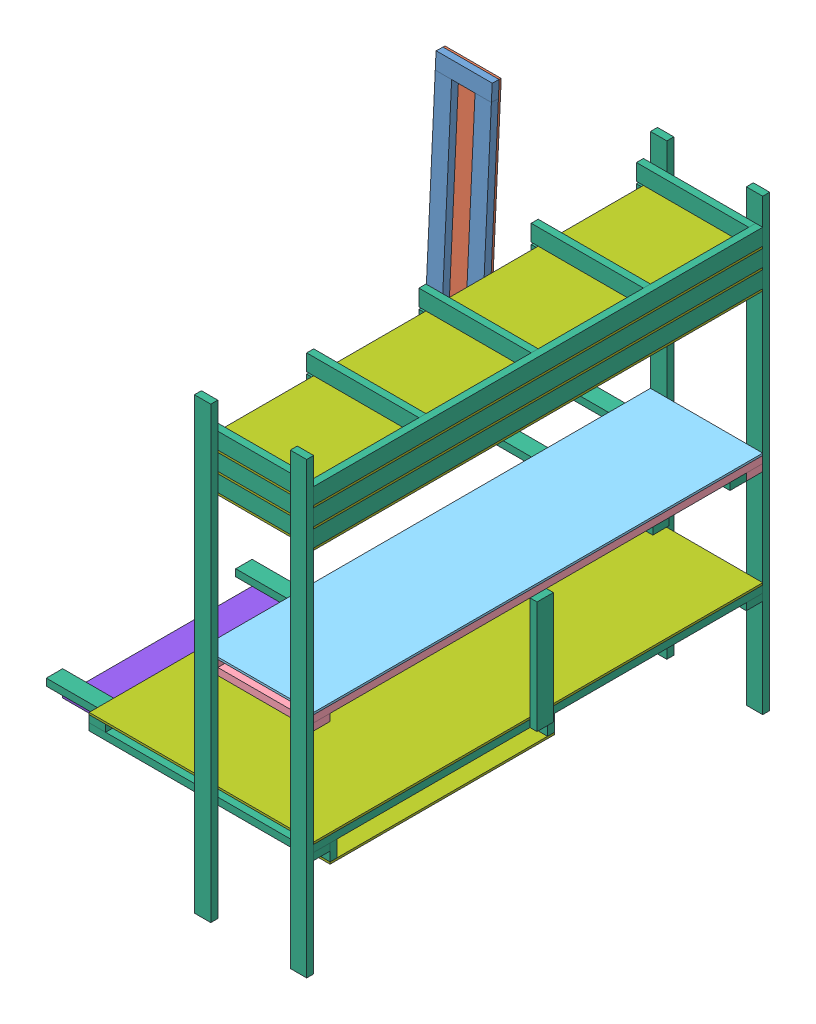
SolidWorks assembly Crafting, configuration Default. Lengths in mm.
Overall size (1623.82 2790.53 2514.6).
67 component instances, 9 part files, 18 mates.
Components (placement in the parent):
- PlotterSupport-1: PlotterSupport [Default] at (-703.0452 -398.7417 -1142.4773) size (304.8 1609.43 541.53)
  - 2x4_Plotter-1: 2x4_Plotter [PlotterWidth] at (215.9 150.676 537.183) x (1 0 0) z (0 0.998805 -0.048876) size (88.9 38.1 1371.6)
  - 2x4_Plotter-2: 2x4_Plotter [PlotterWidth] at (0 150.676 537.183) x (1 0 0) z (0 0.998805 -0.048876) size (88.9 38.1 1371.6)
  - 2x4_Plotter-3: 2x4_Plotter [PlotterDepth] at (304.8 1520.6367 470.144) x (0 0.998805 -0.048876) z (-1 0 0) size (88.9 38.1 304.8)
  - 2x4_Plotter-4: 2x4_Plotter [PlotterDepth] at (0 150.676 537.183) x (0 -0.998805 0.048876) z (1 0 0) size (88.9 38.1 304.8)
  - 2x4_Plotter-5: 2x4_Plotter [PlotterDepth] at (0 0 508) x (0 0 -1) z (1 0 0) size (88.9 38.1 304.8)
  - 2x4_Plotter-6: 2x4_Plotter [PlotterBase] at (215.9 0 88.9) size (88.9 38.1 330.2)
  - 2x4_Plotter-7: 2x4_Plotter [PlotterBase] at (0 0 88.9) size (88.9 38.1 330.2)
  - Plywood_Plotter-1: Plywood_Plotter [PlotterDepth-X-PlotterWidth] at (0 59.4769 492.3744) x (1 0 0) z (0 0.048876 0.998805) size (304.8 1549.4 11.11)
  - Plywood_Plotter-2: Plywood_Plotter [PlotterDepth-X-PlotterBase] at (0 49.2125 0) x (1 0 0) z (0 -1 0) size (304.8 482.6 11.11)
  - Hinge-3: Hinge [Reverse] at (304.8 51.8795 490.076) x (0 0.998805 -0.048876) z (-1 0 0) size (53.98 15.88 101.6)
  - Hinge-4: Hinge [Reverse] at (101.6 51.8795 490.076) x (0 0.998805 -0.048876) z (-1 0 0) size (53.98 15.88 101.6)
  - Hinge-5: Hinge [Default] at (203.2 51.8795 490.076) x (0 0 -1) z (1 0 0) size (53.98 15.88 101.6)
  - Hinge-6: Hinge [Default] at (0 51.8795 490.076) x (0 0 -1) z (1 0 0) size (53.98 15.88 101.6)
  - 2x4_Plotter-9: 2x4_Plotter [PlotterDepth] at (0 0 88.9) x (0 0 -1) z (1 0 0) size (88.9 38.1 304.8)
- Printers-1: Printers [Default] at (259.4601 -401.6094 -1116.5989) x (0 0 1) z (-1 0 0) size (2438.4 87.31 609.6)
  - 2x4_Printers-1: 2x4_Printers [2ft] at (-114.7784 -35.2323 -256.6946) size (88.9 38.1 609.6)
  - 2x4_Printers-2: 2x4_Printers [8ft] at (2323.6216 2.8677 -256.6946) x (0 0 1) z (-1 0 0) size (88.9 38.1 2438.4)
  - 2x4_Printers-3: 2x4_Printers [8ft] at (-114.7784 2.8677 352.9054) x (0 0 -1) z (1 0 0) size (88.9 38.1 2438.4)
  - 2x4_Printers-4: 2x4_Printers [2ft] at (2234.7216 -35.2323 -256.6946) size (88.9 38.1 609.6)
  - Plywood_Printers-1: Plywood_Printers [2ftX8ft] at (2323.6216 52.0802 -256.6946) x (0 0 1) z (0 -1 0) size (609.6 2438.4 11.11)
- 2x4-1: 2x4 [4ft] at (516.1548 -436.8417 -1142.4773) x (0 0 1) z (-1 0 0) size (88.9 38.1 1219.2)
- 2x4-2: 2x4 [4ft] at (516.1548 -436.8417 -723.3773) x (0 0 1) z (-1 0 0) size (88.9 38.1 1219.2)
- LaserCutter-1: LaserCutter [Default] at (-40.6669 -990.6301 -1134.2386) x (0 0 1) z (-1 0 0) size (2438.4 709.61 1623.82)
  - 2x4-1: 2x4 [4ft] at (-97.1386 -55.8116 -556.8217) size (88.9 38.1 1219.2)
  - 2x4-2: 2x4 [8ft] at (2341.2614 -17.7116 -556.8217) x (0 0 1) z (-1 0 0) size (88.9 38.1 2438.4)
  - 2x4-3: 2x4 [4ft] at (2252.3614 -55.8116 -556.8217) size (88.9 38.1 1219.2)
  - 2x4-4: 2x4 [8ft] at (-97.1386 -17.7116 662.3783) x (0 0 -1) z (1 0 0) size (88.9 38.1 2438.4)
  - Plywood-1: Plywood [4ftX8ft] at (2341.2614 31.5009 -556.8217) x (0 0 1) z (0 -1 0) size (1219.2 2438.4 11.11)
  - 2x4-6: 2x4 [2ft] at (1077.6114 -17.7116 -556.8217) x (1 0 0) z (0 1 0) size (88.9 38.1 609.6)
  - 2x4-7: 2x4 [4ft] at (2214.2614 -17.7116 -556.8217) x (0 -1 0) z (0 0 1) size (88.9 38.1 1219.2)
  - Plywood-2: Plywood [4ftX4ft] at (1033.1614 -106.6116 -556.8217) x (1 0 0) z (0 -1 0) size (1219.2 1219.2 11.11)
  - Tray-1: Tray [Default] at (1642.6055 -131.1934 765.8605) x (0 0 1) z (0 1 0) size (698.5 1117.6 49.21)
    - Plywood_LaserCutter-1: Plywood_LaserCutter [Tray] at (-435.4588 -552.4767 24.5819) size (609.6 1117.6 11.11)
    - 2x4_LaserCutter-1: 2x4_LaserCutter [TrayWidth] at (-435.4588 565.1233 35.6944) x (1 0 0) z (0 -1 0) size (88.9 38.1 1117.6)
    - 2x4-2: 2x4 [2ft] at (263.0412 -463.5767 35.6944) x (0 -1 0) z (-1 0 0) size (88.9 38.1 609.6)
    - 2x4-3: 2x4 [2ft] at (-346.5588 476.2233 35.6944) x (0 1 0) z (1 0 0) size (88.9 38.1 609.6)
  - 2x4-9: 2x4 [4ft] at (1033.1614 -17.7116 -556.8217) x (0 -1 0) z (0 0 1) size (88.9 38.1 1219.2)
- 2x4-3: 2x4 [8ft] at (427.2548 858.5583 -1269.4773) x (1 0 0) z (0 -1 0) size (88.9 38.1 2438.4)
- 2x4-4: 2x4 [8ft] at (427.2548 -1579.8417 1245.1227) x (1 0 0) z (0 1 0) size (88.9 38.1 2438.4)
- 2x4-5: 2x4 [8ft] at (-4.5452 -1579.8417 -1269.4773) x (-1 0 0) z (0 1 0) size (88.9 38.1 2438.4)
- 2x4-6: 2x4 [8ft] at (-4.5452 858.5583 1245.1227) x (-1 0 0) z (0 -1 0) size (88.9 38.1 2438.4)
- Stock-3: Stock [Default] at (907.2054 880.5338 42.9548) x (0 0 -1) z (-1 0 0) size (2438.4 300.04 647.7)
  - Shelf-1: Shelf [Default] at (-1191.0865 -104.201 699.3128) size (2438.4 100.01 647.7)
    - Plywood-1: Plywood [2ftX8ft] at (2465.4186 472.2515 -308.2621) x (0 0 1) z (0 -1 0) size (609.6 2438.4 11.11)
    - 2x4-6: 2x4 [8ft] at (27.0186 372.239 -308.2621) x (0 1 0) z (1 0 0) size (88.9 38.1 2438.4)
    - 2x4-7: 2x4 [2ft] at (65.1186 372.239 -270.1621) x (0 1 0) z (0 0 1) size (88.9 38.1 609.6)
    - 2x4-9: 2x4 [2ft] at (674.7186 372.239 -270.1621) x (0 1 0) z (0 0 1) size (88.9 38.1 609.6)
    - 2x4-10: 2x4 [2ft] at (1284.3186 372.239 -270.1621) x (0 1 0) z (0 0 1) size (88.9 38.1 609.6)
    - 2x4-11: 2x4 [2ft] at (1893.9186 372.239 -270.1621) x (0 1 0) z (0 0 1) size (88.9 38.1 609.6)
    - 2x4-12: 2x4 [2ft] at (2427.3186 461.139 -270.1621) x (0 -1 0) z (0 0 1) size (88.9 38.1 609.6)
  - Shelf-2: Shelf [Default] at (-1191.0865 -204.2135 699.3128) size (2438.4 100.01 647.7)
    - Plywood-1: Plywood [2ftX8ft] at (2465.4186 472.2515 -308.2621) x (0 0 1) z (0 -1 0) size (609.6 2438.4 11.11)
    - 2x4-6: 2x4 [8ft] at (27.0186 372.239 -308.2621) x (0 1 0) z (1 0 0) size (88.9 38.1 2438.4)
    - 2x4-7: 2x4 [2ft] at (65.1186 372.239 -270.1621) x (0 1 0) z (0 0 1) size (88.9 38.1 609.6)
    - 2x4-9: 2x4 [2ft] at (674.7186 372.239 -270.1621) x (0 1 0) z (0 0 1) size (88.9 38.1 609.6)
    - 2x4-10: 2x4 [2ft] at (1284.3186 372.239 -270.1621) x (0 1 0) z (0 0 1) size (88.9 38.1 609.6)
    - 2x4-11: 2x4 [2ft] at (1893.9186 372.239 -270.1621) x (0 1 0) z (0 0 1) size (88.9 38.1 609.6)
    - 2x4-12: 2x4 [2ft] at (2427.3186 461.139 -270.1621) x (0 -1 0) z (0 0 1) size (88.9 38.1 609.6)
  - Shelf-3: Shelf [Default] at (-1191.0865 -4.1885 699.3128) size (2438.4 100.01 647.7)
    - Plywood-1: Plywood [2ftX8ft] at (2465.4186 472.2515 -308.2621) x (0 0 1) z (0 -1 0) size (609.6 2438.4 11.11)
    - 2x4-6: 2x4 [8ft] at (27.0186 372.239 -308.2621) x (0 1 0) z (1 0 0) size (88.9 38.1 2438.4)
    - 2x4-7: 2x4 [2ft] at (65.1186 372.239 -270.1621) x (0 1 0) z (0 0 1) size (88.9 38.1 609.6)
    - 2x4-9: 2x4 [2ft] at (674.7186 372.239 -270.1621) x (0 1 0) z (0 0 1) size (88.9 38.1 609.6)
    - 2x4-10: 2x4 [2ft] at (1284.3186 372.239 -270.1621) x (0 1 0) z (0 0 1) size (88.9 38.1 609.6)
    - 2x4-11: 2x4 [2ft] at (1893.9186 372.239 -270.1621) x (0 1 0) z (0 0 1) size (88.9 38.1 609.6)
    - 2x4-12: 2x4 [2ft] at (2427.3186 461.139 -270.1621) x (0 -1 0) z (0 0 1) size (88.9 38.1 609.6)
Mates (geometry in assembly coordinates):
- Coincident1: coincident anti-aligned: plane of Printers-1/2x4_Printers-2 through (516.1548 -398.7417 -1231.3773) normal (0 -1 0); plane of 2x4-1 through (-703.0452 -398.7417 -1142.4773) normal (0 1 0)
- Coincident2: coincident anti-aligned: plane of Printers-1/2x4_Printers-1 through (-93.4452 -436.8417 -1142.4773) normal (0 0 1); plane of 2x4-1 through (-703.0452 -436.8417 -1142.4773) normal (0 0 -1)
- Coincident3: coincident aligned: plane of Printers-1/2x4_Printers-1 through (516.1548 -436.8417 -1231.3773) normal (1 0 0); plane of 2x4-1 through (516.1548 -436.8417 -1142.4773) normal (1 0 0)
- Coincident4: coincident anti-aligned: plane of Printers-1/2x4_Printers-2 through (516.1548 -398.7417 -1231.3773) normal (0 -1 0); plane of 2x4-2 through (-703.0452 -398.7417 -723.3773) normal (0 1 0)
- Coincident5: coincident aligned: plane of Printers-1/2x4_Printers-2 through (516.1548 -398.7417 -1231.3773) normal (1 0 0); plane of 2x4-2 through (516.1548 -436.8417 -723.3773) normal (1 0 0)
- Coincident9: coincident aligned: plane of PlotterSupport-1/2x4_Plotter-5 through (-398.2452 -398.7417 -634.4773) normal (0 0 1); plane of 2x4-2 through (-703.0452 -436.8417 -634.4773) normal (0 0 1)
- Coincident10: coincident anti-aligned: plane of PlotterSupport-1/2x4_Plotter-9 through (-398.2452 -398.7417 -1053.5773) normal (0 -1 0); plane of 2x4-1 through (-703.0452 -398.7417 -1142.4773) normal (0 1 0)
- Coincident11: coincident aligned: plane of PlotterSupport-1/2x4_Plotter-9 through (-703.0452 -398.7417 -1053.5773) normal (-1 0 0); plane of 2x4-1 through (-703.0452 -436.8417 -1142.4773) normal (-1 0 0)
- Distance1: distance = 609.6 mm aligned: plane of Printers-1/Plywood_Printers-1 through (516.1548 -349.5292 1207.0227) normal (0 1 0); plane of LaserCutter-1/Plywood-1 through (516.1548 -959.1292 1207.0227) normal (0 1 0)
- Coincident18: coincident aligned: plane of PlotterSupport-1/2x4_Plotter-9 through (-398.2452 -398.7417 -1142.4773) normal (0 0 -1); plane of 2x4-1 through (-703.0452 -436.8417 -1142.4773) normal (0 0 -1)
- Coincident19: coincident aligned: plane of Printers-1/2x4_Printers-2 through (516.1548 -398.7417 -1231.3773) normal (1 0 0); plane of LaserCutter-1/2x4-2 through (516.1548 -1008.3417 -1231.3773) normal (1 0 0)
- Coincident20: coincident aligned: plane of Printers-1/2x4_Printers-2 through (516.1548 -398.7417 -1231.3773) normal (0 0 -1); plane of LaserCutter-1/2x4-2 through (516.1548 -1008.3417 -1231.3773) normal (0 0 -1)
- Coincident21: coincident anti-aligned: plane of LaserCutter-1/2x4-1 through (-703.0452 -1046.4417 -1231.3773) normal (0 0 -1); plane of 2x4-3 through (427.2548 -1579.8417 -1231.3773) normal (0 0 1)
- Coincident22: coincident aligned: plane of LaserCutter-1/2x4-2 through (427.2548 -1008.3417 -1231.3773) normal (-1 0 0); plane of 2x4-3 through (427.2548 -1579.8417 -1269.4773) normal (-1 0 0)
- Distance3: distance = 609.6 mm aligned: plane of 2x4-3 through (427.2548 -1579.8417 -1269.4773) normal (0 -1 0); plane of LaserCutter-1/Plywood-1 through (516.1548 -970.2417 1207.0227) normal (0 -1 0)
- Distance4: distance = 762 mm anti-aligned: plane of Stock-3/Shelf-3/Plywood-1 through (516.1548 412.4708 -1231.3773) normal (0 -1 0); plane of Printers-1/Plywood_Printers-1 through (516.1548 -349.5292 1207.0227) normal (0 1 0)
- Coincident28: coincident anti-aligned: plane of 2x4-5 through (-4.5452 858.5583 -1231.3773) normal (0 0 1); plane of Stock-3/Shelf-3/2x4-12 through (-131.5452 423.5833 -1231.3773) normal (0 0 -1)
- Coincident29: coincident aligned: plane of 2x4-3 through (516.1548 -1579.8417 -1269.4773) normal (1 0 0); plane of Stock-3/Shelf-3/2x4-6 through (516.1548 512.4833 -1231.3773) normal (1 0 0)
